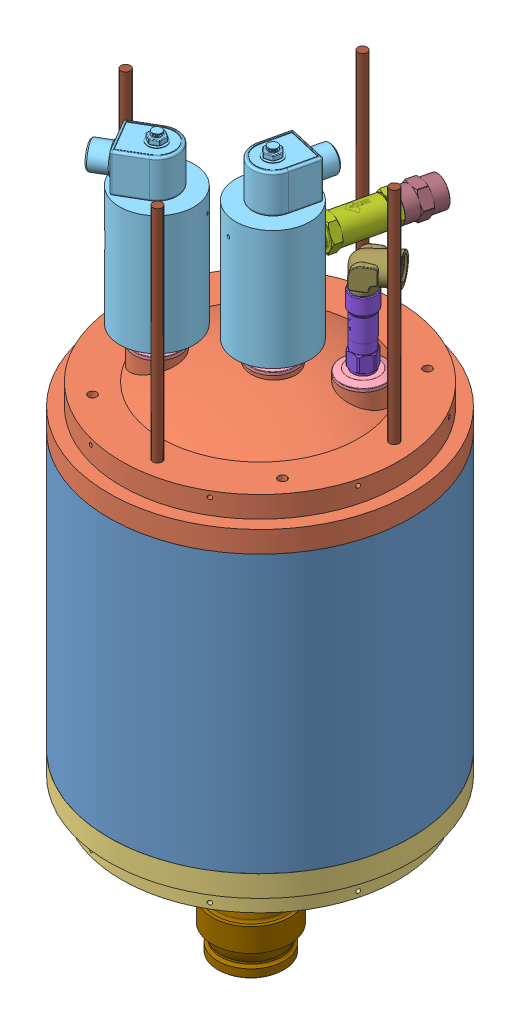
SolidWorks assembly 000054-R02_LNG_TANK_ASSM, configuration Default. Lengths in mm.
Overall size (416.65 703.78 416.65).
24 component instances, 13 part files, 37 mates.
Components (placement in the parent):
- 000056-R02_LNG_TANK_WALL-1: 000056-R02_LNG_TANK_WALL [Default] x (0.895343 0 -0.445376) z (0.445376 0 0.895343) size (304.8 279.4 304.8)
- 000052-R02a_TANK_BULKHEAD_TOP-1: 000052-R02a_TANK_BULKHEAD_TOP [Default] at (0 279.4 0) x (0.864741 0 -0.502217) z (0.502217 0 0.864741) size (304.8 66.04 304.8)
- 000052-R02b_TANK_BULKHEAD_BOTTOM-2: 000052-R02b_TANK_BULKHEAD_BOTTOM [Default] x (-0.502217 0 -0.864741) z (-0.864741 0 0.502217) size (304.8 66.04 304.8)
- FUELTANKPARTS-1-2-AL-FITTING-1: FUELTANKPARTS-1-2-AL-FITTING [Default] at (8.2367 338.582 -4.7836) x (0.997569 0 -0.069681) z (0.069681 0 0.997569) size (44.96 12.45 44.96)
- FUELTANKPARTS-1-2-AL-FITTING-2: FUELTANKPARTS-1-2-AL-FITTING [Default] at (65.8933 336.042 -38.269) x (0.65902 0 -0.752126) z (0.752126 0 0.65902) size (44.96 12.45 44.96)
- FUELTANKPARTS-1-2-AL-FITTING-6: FUELTANKPARTS-1-2-AL-FITTING [Default] at (-38.269 -56.642 -65.8933) x (0.837169 0 0.546944) z (0.546944 0 -0.837169) size (44.96 12.45 44.96)
- FUELTANKPARTS-1-2-AL-FITTING-7: FUELTANKPARTS-1-2-AL-FITTING [Default] at (12.7563 -59.182 21.9644) x (-0.715018 0 -0.699106) z (-0.699106 0 0.715018) size (44.96 12.45 44.96)
- FUELTANKPARTS-1-2-AL-FITTING-11: FUELTANKPARTS-1-2-AL-FITTING [Default] at (-38.269 336.042 -65.8933) x (-0.752126 0 -0.65902) z (0.65902 0 -0.752126) size (44.96 12.45 44.96)
- FUELTANKPARTS-1-2-AL-FITTING-12: FUELTANKPARTS-1-2-AL-FITTING [Default] at (-65.8933 336.042 38.269) x (-0.65902 0 0.752126) z (-0.752126 0 -0.65902) size (44.96 12.45 44.96)
- EH50-08-D024-OXXP-1: EH50-08-D024-OXXP [Default] at (8.2367 438.3278 -4.7836) x (0.224484 0 -0.974478) z (0.974478 0 0.224484) size (87.5 168.84 74.93)
- cryo-pducer-temp-1: cryo-pducer-temp [Default] at (-38.269 338.328 -65.8933) size (25.65 83.82 25.65)
- TIN20021-1: TIN20021 [Default] at (31.1868 438.3278 -104.4093) x (-0.224484 0 0.974478) z (0.974448 -0.007817 0.224477) size (102.11 28.58 33)
- CRVP4-500B-1: CRVP4-500B [Default] at (65.8933 336.042 -38.269) x (0 1 0) z (-0.024117 0 0.999709) size (82.27 25.15 25.15)
- atomatik-2: atomatik [Default] at (12.7563 -128.3301 21.9644) x (0 1 0) z (-0.491272 0 0.871006) size (76.23 180.98 78)
- 44665K173_STANDARD-WALL ALUMINUM THREADED PIPE NIPPLE-1: 44665K173_STANDARD-WALL ALUMINUM THREADED PIPE NIPPLE [44665K173] at (-65.8933 354.0379 38.269) x (1 0 0) z (0 1 0) size (22.19 22.36 51.97)
- 44665K173_STANDARD-WALL ALUMINUM THREADED PIPE NIPPLE-2: 44665K173_STANDARD-WALL ALUMINUM THREADED PIPE NIPPLE [44665K173] at (8.2367 356.5779 -4.7836) x (1 0 0) z (0 1 0) size (22.19 22.36 51.97)
- 44665K173_STANDARD-WALL ALUMINUM THREADED PIPE NIPPLE-3: 44665K173_STANDARD-WALL ALUMINUM THREADED PIPE NIPPLE [44665K173] at (12.7563 -77.1779 21.9644) x (0.980261 0 0.197708) z (0 1 0) size (22.19 22.36 51.97)
- MCMASTER_94435A523_9in-1: MCMASTER_94435A523_9in [Default] at (-16.0544 316.23 -119.5771) x (0 1 0) z (0.780678 0 -0.624933) size (228.6 9.53 9.53)
- MCMASTER_94435A523_9in-3: MCMASTER_94435A523_9in [Default] at (-119.5771 316.23 16.0544) x (0 1 0) z (-0.624933 0 -0.780678) size (228.6 9.53 9.53)
- MCMASTER_94435A523_9in-4: MCMASTER_94435A523_9in [Default] at (16.0544 316.23 119.5771) x (0 1 0) z (-0.780678 0 0.624933) size (228.6 9.53 9.53)
- MCMASTER_94435A523_9in-5: MCMASTER_94435A523_9in [Default] at (119.5771 316.23 -16.0544) x (0 1 0) z (0.624933 0 0.780678) size (228.6 9.53 9.53)
- 3861T240_MED-PRESSURE ANODIZED ALUM THRD PIPE FITTING-2: 3861T240_MED-PRESSURE ANODIZED ALUM THRD PIPE FITTING [3861T24] at (91.3176 439.3406 -53.7479) x (0.520028 0 0.854149) z (0.854149 0 -0.520028) size (30.97 56.51 41.63)
- 51205K223_EXTREME-PRESSURE 316 SS THREADED PIPE FITTING-1: 51205K223_EXTREME-PRESSURE 316 SS THREADED PIPE FITTING [51205K223] at (35.4632 438.3278 -122.9732) x (-0.827824 -0.52758 -0.190701) z (-0.224484 0 0.974478) size (28.7 32.74 38.1)
- EH50-08-D024-OXXP-2: EH50-08-D024-OXXP [Default] at (-65.8933 435.7878 38.269) x (-0.861847 0 0.507168) z (-0.507168 0 -0.861847) size (87.5 168.84 74.93)
Mates (geometry in assembly coordinates):
- Coincident1: coincident anti-aligned: line of 000056-R02_LNG_TANK_WALL-1 through (279.4 0 279.4) axis (0 0 -1); line of 000052-R02a_TANK_BULKHEAD_TOP-1 through (0 229.5587 0) axis (0 1 0)
- Coincident2: coincident anti-aligned: plane of 000056-R02_LNG_TANK_WALL-1 through (0 279.4 0) normal (0 1 0); plane of 000052-R02a_TANK_BULKHEAD_TOP-1 through (126.2955 279.4 -73.3488) normal (0 -1 0)
- Coincident3: coincident aligned: line of 000056-R02_LNG_TANK_WALL-1 through (279.4 0 279.4) axis (0 0 -1); line of 000052-R02b_TANK_BULKHEAD_BOTTOM-2 through (0 0 0) axis (0 -1 0)
- Coincident4: coincident anti-aligned: plane of 000056-R02_LNG_TANK_WALL-1 through (0 0 0) normal (0 -1 0); plane of 000052-R02b_TANK_BULKHEAD_BOTTOM-2 through (-73.3488 0 -126.2955) normal (0 1 0)
- Coincident10: coincident anti-aligned: plane of 000052-R02a_TANK_BULKHEAD_TOP-1 through (8.2367 345.44 -4.7836) normal (0 1 0); plane of FUELTANKPARTS-1-2-AL-FITTING-1 through (8.2367 345.44 -4.7836) normal (0 -1 0)
- Concentric6: concentric anti-aligned: cylinder of 000052-R02b_TANK_BULKHEAD_BOTTOM-2 through (12.7563 -66.04 21.9644) axis (0 -1 0) radius 12.7; cylinder of FUELTANKPARTS-1-2-AL-FITTING-7 through (12.7563 -66.04 21.9644) axis (0 1 0) radius 12.7
- Coincident11: coincident anti-aligned: plane of 000052-R02b_TANK_BULKHEAD_BOTTOM-2 through (12.7563 -66.04 21.9644) normal (0 -1 0); plane of FUELTANKPARTS-1-2-AL-FITTING-7 through (12.7563 -66.04 21.9644) normal (0 1 0)
- Concentric8: concentric anti-aligned: cylinder of 000052-R02b_TANK_BULKHEAD_BOTTOM-2 through (-38.269 -63.5 -65.8933) axis (0 -1 0) radius 12.7; cylinder of FUELTANKPARTS-1-2-AL-FITTING-6 through (-38.269 -63.5 -65.8933) axis (0 1 0) radius 12.7
- Coincident12: coincident anti-aligned: plane of 000052-R02b_TANK_BULKHEAD_BOTTOM-2 through (-38.269 -63.5 -65.8933) normal (0 -1 0); plane of FUELTANKPARTS-1-2-AL-FITTING-6 through (-38.269 -63.5 -65.8933) normal (0 1 0)
- Concentric11: concentric anti-aligned: cylinder of 000052-R02a_TANK_BULKHEAD_TOP-1 through (-38.269 342.9 -65.8933) axis (0 1 0) radius 12.7; cylinder of 000052-R02b_TANK_BULKHEAD_BOTTOM-2 through (-38.269 -63.5 -65.8933) axis (0 -1 0) radius 12.7
- Concentric12: concentric anti-aligned: cylinder of 000052-R02a_TANK_BULKHEAD_TOP-1 through (65.8933 342.9 -38.269) axis (0 1 0) radius 12.7; cylinder of FUELTANKPARTS-1-2-AL-FITTING-2 through (65.8933 348.488 -38.269) axis (0 -1 0) radius 9.271
- Coincident14: coincident anti-aligned: plane of 000052-R02a_TANK_BULKHEAD_TOP-1 through (65.8933 342.9 -38.269) normal (0 1 0); plane of FUELTANKPARTS-1-2-AL-FITTING-2 through (65.8933 342.9 -38.269) normal (0 -1 0)
- Concentric14: concentric anti-aligned: cylinder of FUELTANKPARTS-1-2-AL-FITTING-1 through (8.2367 351.028 -4.7836) axis (0 -1 0) radius 9.271; cone of EH50-08-D024-OXXP-1 through (8.2367 362.1278 -4.7836) axis (0 1 0)
- Concentric15: concentric aligned: cylinder of FUELTANKPARTS-1-2-AL-FITTING-11 through (-38.269 348.488 -65.8933) axis (0 -1 0) radius 9.271; cylinder of cryo-pducer-temp-1 through (-38.269 338.328 -65.8933) axis (0 -1 0) radius 8.89
- Distance2: distance = 2.54 mm anti-aligned: plane of cryo-pducer-temp-1 through (-26.839 351.028 -65.8933) normal (0 -1 0); plane of FUELTANKPARTS-1-2-AL-FITTING-11 through (-38.269 348.488 -65.8933) normal (0 1 0)
- Concentric16: concentric anti-aligned: cylinder of 000052-R02a_TANK_BULKHEAD_TOP-1 through (8.2367 345.44 -4.7836) axis (0 1 0) radius 12.7; cylinder of FUELTANKPARTS-1-2-AL-FITTING-1 through (8.2367 351.028 -4.7836) axis (0 -1 0) radius 9.271
- Concentric21: concentric aligned: cone of EH50-08-D024-OXXP-1 through (15.8487 438.3278 -37.8272) axis (-0.224484 0 0.974478); cone of TIN20021-1 through (16.9534 438.3278 -42.6228) axis (-0.224484 0 0.974478)
- Distance4: distance = 6.35 mm anti-aligned: plane of EH50-08-D024-OXXP-1 through (15.8487 454.2028 -37.8272) normal (0.224484 0 -0.974478); plane of TIN20021-1 through (9.2361 438.3923 -45.8668) normal (-0.224484 0 0.974478)
- Concentric24: concentric aligned: cylinder of FUELTANKPARTS-1-2-AL-FITTING-2 through (65.8933 348.488 -38.269) axis (0 -1 0) radius 9.271; cone of CRVP4-500B-1 through (65.8933 351.028 -38.269) axis (0 -1 0)
- Distance5: distance = 2.54 mm anti-aligned: plane of CRVP4-500B-1 through (65.8933 351.028 -38.269) normal (0 -1 0); plane of FUELTANKPARTS-1-2-AL-FITTING-2 through (65.8933 348.488 -38.269) normal (0 1 0)
- Concentric36: concentric anti-aligned: cylinder of FUELTANKPARTS-1-2-AL-FITTING-12 through (-65.8933 348.488 38.269) axis (0 -1 0) radius 9.271; cylinder of 44665K173_STANDARD-WALL ALUMINUM THREADED PIPE NIPPLE-1 through (-65.8933 348.488 38.269) axis (0 1 0) radius 10.668
- Coincident36: coincident aligned: plane of FUELTANKPARTS-1-2-AL-FITTING-12 through (-65.8933 348.488 38.269) normal (0 1 0); circle of 44665K173_STANDARD-WALL ALUMINUM THREADED PIPE NIPPLE-1
- Concentric38: concentric anti-aligned: cylinder of FUELTANKPARTS-1-2-AL-FITTING-1 through (8.2367 351.028 -4.7836) axis (0 -1 0) radius 9.271; cylinder of 44665K173_STANDARD-WALL ALUMINUM THREADED PIPE NIPPLE-2 through (8.2367 351.028 -4.7836) axis (0 1 0) radius 10.668
- Coincident38: coincident aligned: plane of FUELTANKPARTS-1-2-AL-FITTING-1 through (8.2367 351.028 -4.7836) normal (0 1 0); circle of 44665K173_STANDARD-WALL ALUMINUM THREADED PIPE NIPPLE-2
- Coincident39: coincident aligned: plane of EH50-08-D024-OXXP-1 through (8.9494 362.1278 -7.8776) normal (0 -1 0); circle of 44665K173_STANDARD-WALL ALUMINUM THREADED PIPE NIPPLE-2
- Concentric39: concentric aligned: cylinder of FUELTANKPARTS-1-2-AL-FITTING-7 through (12.7563 -71.628 21.9644) axis (0 1 0) radius 9.271; cylinder of 44665K173_STANDARD-WALL ALUMINUM THREADED PIPE NIPPLE-3 through (12.7563 -82.7278 21.9644) axis (0 1 0) radius 10.668
- Coincident40: coincident aligned: plane of FUELTANKPARTS-1-2-AL-FITTING-7 through (12.7563 -71.628 21.9644) normal (0 -1 0); circle of 44665K173_STANDARD-WALL ALUMINUM THREADED PIPE NIPPLE-3
- Coincident41: coincident aligned: plane of atomatik-2 through (32.8983 -82.7278 33.3251) normal (0 1 0); circle of 44665K173_STANDARD-WALL ALUMINUM THREADED PIPE NIPPLE-3
- Concentric40: concentric anti-aligned: cylinder of atomatik-2 through (12.7563 -103.6994 21.9644) axis (0 -1 0) radius 16.775; cylinder of 44665K173_STANDARD-WALL ALUMINUM THREADED PIPE NIPPLE-3 through (12.7563 -82.7278 21.9644) axis (0 1 0) radius 10.668
- Concentric41: concentric anti-aligned: cylinder of 000052-R02a_TANK_BULKHEAD_TOP-1 through (-16.0544 322.58 -119.5771) axis (0 1 0) radius 4.2164; cylinder of MCMASTER_94435A523_9in-1 through (-16.0544 544.83 -119.5771) axis (0 -1 0) radius 4.7625
- Distance6: distance = 6.35 mm anti-aligned: plane of MCMASTER_94435A523_9in-1 through (-16.0544 316.23 -119.5771) normal (0 -1 0); plane of 000052-R02a_TANK_BULKHEAD_TOP-1 through (120.8044 322.58 -70.1598) normal (0 1 0)
- Concentric43: concentric anti-aligned: cylinder of CRVP4-500B-1 through (65.8933 389.382 -38.269) axis (0 1 0) radius 7.9375; cylinder of 3861T240_MED-PRESSURE ANODIZED ALUM THRD PIPE FITTING-2 through (65.8933 421.4812 -38.269) axis (0 -1 0) radius 6.7469
- Coincident43: coincident anti-aligned: plane of CRVP4-500B-1 through (65.8933 418.3126 -38.269) normal (0 1 0); plane of 3861T240_MED-PRESSURE ANODIZED ALUM THRD PIPE FITTING-2 through (42.7961 418.3126 -41.8632) normal (0 -1 0)
- Concentric44: concentric anti-aligned: cylinder of TIN20021-1 through (33.4391 438.3278 -114.1863) axis (0.224484 0 -0.974478) radius 5.2388; cylinder of 51205K223_EXTREME-PRESSURE 316 SS THREADED PIPE FITTING-1 through (31.1868 438.3278 -104.4093) axis (-0.224484 0 0.974478) radius 6.35
- Coincident44: coincident anti-aligned: plane of TIN20021-1 through (23.1487 438.3923 -106.261) normal (0.224484 0 -0.974478); plane of 51205K223_EXTREME-PRESSURE 316 SS THREADED PIPE FITTING-1 through (31.1868 438.3278 -104.4093) normal (-0.224484 0 0.974478)
- Concentric45: concentric aligned: cylinder of 44665K173_STANDARD-WALL ALUMINUM THREADED PIPE NIPPLE-1 through (-65.8933 348.488 38.269) axis (0 1 0) radius 10.668; cone of EH50-08-D024-OXXP-2 through (-65.8933 359.5878 38.269) axis (0 1 0)
- Coincident46: coincident aligned: circle of 44665K173_STANDARD-WALL ALUMINUM THREADED PIPE NIPPLE-1; plane of EH50-08-D024-OXXP-2 through (-68.6297 359.5878 39.8792) normal (0 -1 0)
